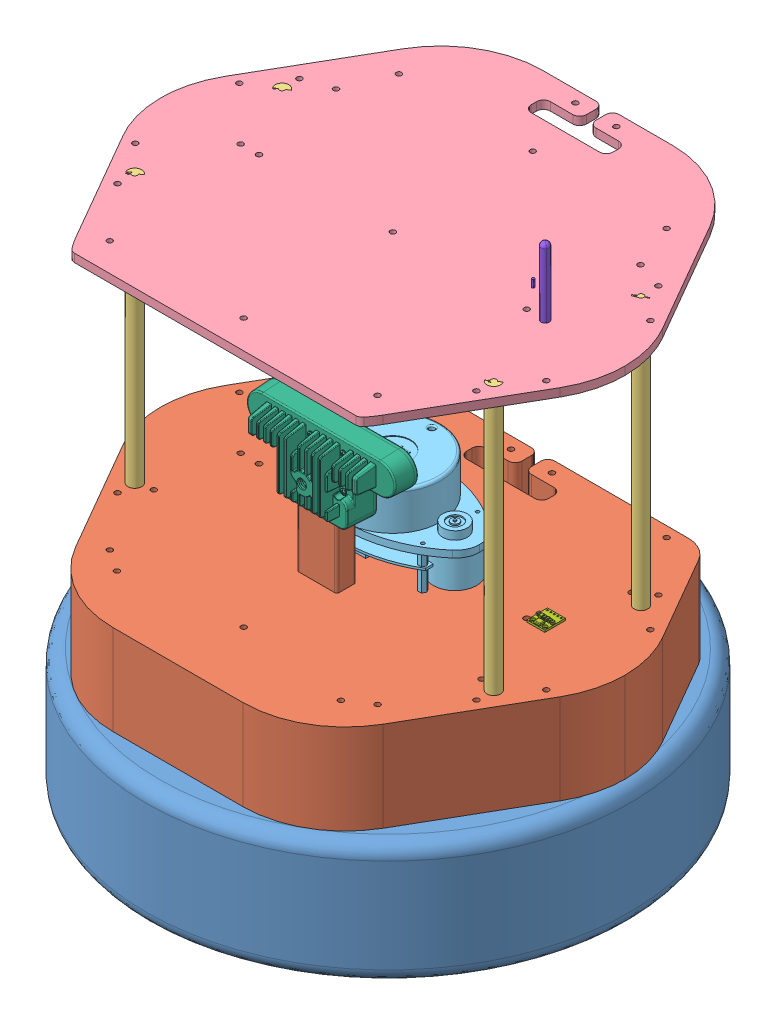
SolidWorks assembly Turtlebot Assem, configuration Default. Lengths in mm.
Overall size (354 401 354).
11 component instances, 8 part files, 25 mates.
Components (placement in the parent):
- Kobuki Base-1: Kobuki Base [Default] at (151.4984 129.222 268.9926) size (354 89 354)
- Layer A-1: Layer A [Default] at (151.4984 278.222 265.3926) size (340 111 267.27)
- ROD-1: ROD [Default] at (282.8984 218.222 322.8926) x (-0.326124 0 0.945327) z (-0.945327 0 -0.326124) size (10 262 10)
- ROD-2: ROD [Default] at (282.8984 218.222 215.0926) x (0.242222 0 0.970221) z (-0.970221 0 0.242222) size (10 262 10)
- ROD-3: ROD [Default] at (20.0984 218.222 322.8926) x (0.560447 0 0.828191) z (-0.828191 0 0.560447) size (10 262 10)
- ROD-4: ROD [Default] at (20.0984 218.222 215.0926) size (10 262 10)
- Layer C-1: Layer C [Default] at (151.4984 474.222 265.3926) size (340 6 287.27)
- rplidar_main-1: rplidar_main [По умолчанию] at (165.7484 308.822 265.3942) size (98.5 57.7 70.02)
- OAK-D-parts-14sep2020.stp-3: OAK-D-parts-14sep2020.stp [Default] at (149.808 370.0152 305.3942) x (-1 0 0) z (0 0 -1) size (110 54.5 33.05)
- OSNOVANIE.stp-1: OSNOVANIE.stp [Default] at (251.9304 284.222 252.7128) x (0.999998 0 -0.001829) z (0 1 0) size (13.1 15 3.05)
- ds18b20.step-1: ds18b20.step [Default] at (262.9536 505.222 265.3927) x (-0.837169 0 -0.546944) z (0 1 0) size (34.1 6 75.95)
Mates (geometry in assembly coordinates):
- Concentric1: concentric anti-aligned: cylinder of Kobuki Base-1 through (282.8984 199.222 215.0926) axis (0 1 0) radius 1.975; cylinder of Layer A-1 through (282.8984 218.222 215.0926) axis (0 -1 0) radius 1.9748
- Concentric2: concentric anti-aligned: cylinder of Kobuki Base-1 through (282.8984 199.222 322.8926) axis (0 1 0) radius 1.975; cylinder of Layer A-1 through (282.8984 218.222 322.8926) axis (0 -1 0) radius 1.9748
- Concentric3: concentric anti-aligned: cylinder of Kobuki Base-1 through (282.8984 199.222 322.8926) axis (0 1 0) radius 1.975; cylinder of ROD-1 through (282.8984 480.222 322.8926) axis (0 -1 0) radius 5
- Coincident1: coincident anti-aligned: plane of Kobuki Base-1 through (151.4984 218.222 268.9926) normal (0 1 0); plane of ROD-1 through (282.8984 218.222 322.8926) normal (0 -1 0)
- Concentric4: concentric anti-aligned: cylinder of Kobuki Base-1 through (282.8984 199.222 215.0926) axis (0 1 0) radius 1.975; cylinder of ROD-2 through (282.8984 480.222 215.0926) axis (0 -1 0) radius 5
- Coincident2: coincident anti-aligned: plane of Kobuki Base-1 through (151.4984 218.222 268.9926) normal (0 1 0); plane of ROD-2 through (282.8984 218.222 215.0926) normal (0 -1 0)
- Concentric5: concentric anti-aligned: circle of Kobuki Base-1; cylinder of ROD-3 through (20.0984 480.222 322.8926) axis (0 -1 0) radius 5
- Coincident3: coincident anti-aligned: plane of Kobuki Base-1 through (151.4984 218.222 268.9926) normal (0 1 0); plane of ROD-3 through (20.0984 218.222 322.8926) normal (0 -1 0)
- Coincident4: coincident anti-aligned: plane of Kobuki Base-1 through (151.4984 218.222 268.9926) normal (0 1 0); plane of ROD-4 through (20.0984 218.222 215.0926) normal (0 -1 0)
- Concentric6: concentric anti-aligned: cylinder of Kobuki Base-1 through (20.0984 199.222 215.0926) axis (0 1 0) radius 1.975; cylinder of ROD-4 through (20.0984 480.222 215.0926) axis (0 -1 0) radius 5
- Distance1: distance = 155 mm anti-aligned: plane of Layer A-1 through (-15.9458 284.222 245.9812) normal (0 1 0); plane of Kobuki Base-1 through (151.4984 129.222 268.9926) normal (0 -1 0)
- Concentric8: concentric aligned: cylinder of ROD-2 through (282.8984 480.222 215.0926) axis (0 -1 0) radius 5; cylinder of Layer C-1 through (282.8984 474.222 215.0926) axis (0 -1 0) radius 1.9748
- Concentric9: concentric aligned: cylinder of ROD-1 through (282.8984 480.222 322.8926) axis (0 -1 0) radius 5; cylinder of Layer C-1 through (282.8984 474.222 322.8926) axis (0 -1 0) radius 1.9748
- Distance2: distance = 351 mm anti-aligned: plane of Layer C-1 through (260.6195 480.222 390.4182) normal (0 1 0); plane of Kobuki Base-1 through (151.4984 129.222 268.9926) normal (0 -1 0)
- Concentric10: concentric anti-aligned: circle of Layer A-1; circle of rplidar_main-1
- Coincident5: coincident anti-aligned: plane of Layer A-1 through (-15.9458 284.222 245.9812) normal (0 1 0); plane of rplidar_main-1 through (165.7484 284.222 265.3942) normal (0 -1 0)
- Parallel1: parallel anti-aligned: plane of Layer A-1 through (121.4984 284.222 186.3926) normal (1 0 0); plane of rplidar_main-1 through (141.6502 293.222 295.3942) normal (-1 0 0)
- Coincident10: coincident: plane of rplidar_main-1 through (116.4984 313.822 300.3942) normal (0 0 1); plane of OAK-D-parts-14sep2020.stp-3 through (192.808 370.0152 300.3942) normal (0 0 -1)
- Tangent1: tangent: circle of rplidar_main-1; plane of OAK-D-parts-14sep2020.stp-3 through (192.808 370.0152 300.3942) normal (0 0 -1)
- Coincident17: coincident: line of Layer A-1 through (135.0875 329.222 317.6581) axis (0.001829 0 -0.999998); line of OAK-D-parts-14sep2020.stp-3 through (135.0875 329.222 317.6581) axis (0.001829 0 -0.999998)
- Concentric12: concentric anti-aligned: circle of Layer A-1; cylinder of OSNOVANIE.stp-1 through (262.9536 284.222 265.3927) axis (0 1 0) radius 1.5
- Coincident18: coincident anti-aligned: plane of Layer A-1 through (-15.9458 284.222 245.9812) normal (0 1 0); plane of OSNOVANIE.stp-1 through (258.4941 284.222 260.2008) normal (0 -1 0)
- Parallel7: parallel aligned: plane of Layer A-1 through (164.5286 362.0354 317.6581) normal (0.999998 0 -0.001829); plane of OSNOVANIE.stp-1 through (265.0578 284.222 267.6888) normal (0.999998 0 -0.001829)
- Concentric13: concentric aligned: circle of Layer C-1; circle of ds18b20.step-1
- Coincident20: coincident aligned: plane of Layer C-1 through (260.6195 480.222 390.4182) normal (0 1 0); circle of ds18b20.step-1
